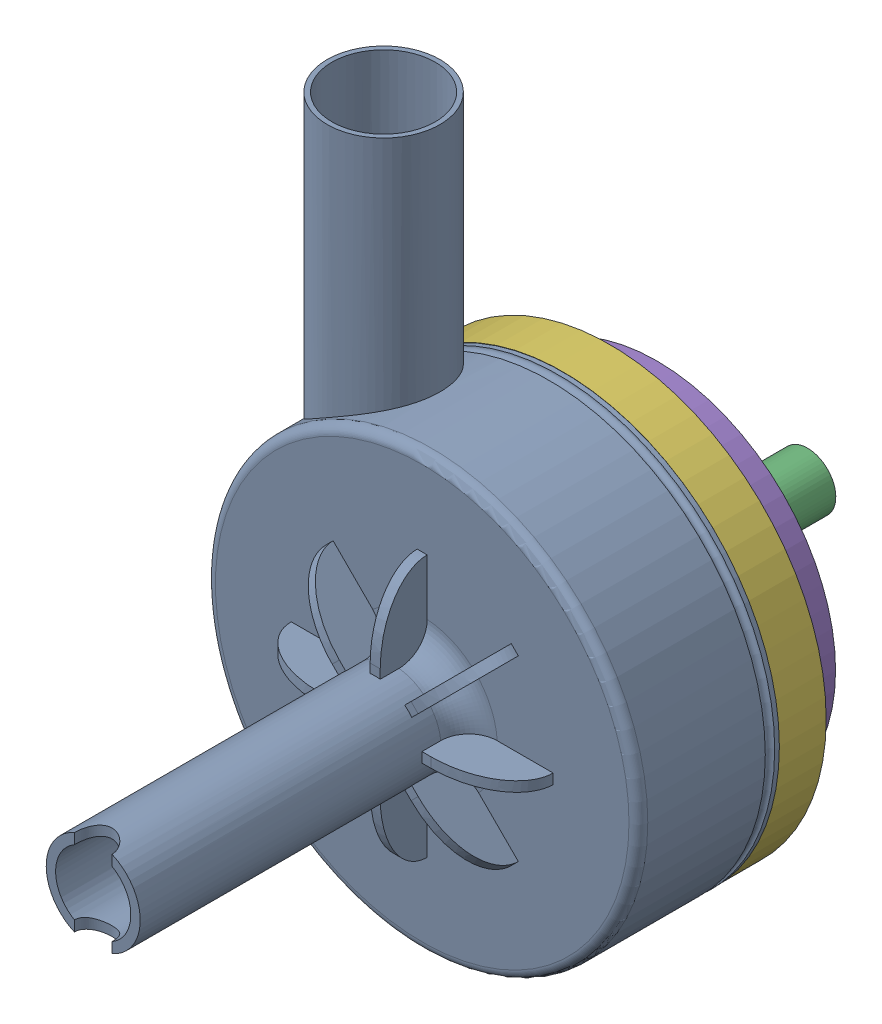
SolidWorks assembly bomba backup all, configuration Default. Lengths in mm.
Overall size (46.06 70 76.13).
5 component instances, 5 part files, 10 mates.
Components (placement in the parent):
- bomba backup-1: bomba backup [Default] at (13.3731 0.3518 -7.2958) size (46 70 50.15)
- hélice backup-1: hélice backup [Default] at (13.3731 0.3518 -5.2958) x (0.145388 -0.989375 0) z (-0.989375 -0.145388 0) size (37.44 12 37.44)
- veio backup-1: veio backup [Default] at (13.3731 0.3518 6.7042) x (-0.145388 0.989375 0) z (0 0 -1) size (6 6 40)
- tampa backup-1: tampa backup [Default] at (13.3493 0.3788 -7.2958) x (-0.999999 0.001285 0) z (0 0 -1) size (46 46 15.02)
- dummy backup-1: dummy backup [Default] at (13.3731 0.3518 -7.2958) x (0.999769 0.021513 0) z (0 0 1) size (38 38 14) (hidden)
Mates (geometry in assembly coordinates):
- Concentric1: concentric aligned: cylinder of bomba backup-1 through (13.3731 0.3518 5.7042) axis (0 0 1) radius 4; cylinder of hélice-1 through (13.3731 0.3518 -5.2958) axis (0 0 1) radius 3
- Coincident1: coincident anti-aligned: plane of bomba backup-1 through (13.3731 0.3518 6.7042) normal (0 0 -1); plane of hélice-1 through (31.1518 2.9764 6.7042) normal (0 0 1)
- Concentric3: concentric aligned: cylinder of hélice-1 through (13.3731 0.3518 -5.2958) axis (0 0 1) radius 3; cylinder of veio backup-1 through (13.3731 0.3518 -33.2958) axis (0 0 1) radius 3
- Coincident3: coincident anti-aligned: plane of hélice-1 through (15.0268 2.8549 -5.2958) normal (-0.989375 -0.145388 0); plane of veio backup-1 through (15.0268 2.8549 -33.2958) normal (0.989375 0.145388 0)
- Coincident4: coincident anti-aligned: plane of hélice-1 through (31.1518 2.9764 -5.2958) normal (0 0 -1); plane of veio backup-1 through (13.3731 0.3518 -5.2958) normal (0 0 1)
- Concentric4: concentric anti-aligned: cylinder of bomba backup-1 through (34.3493 0.3518 -2.2958) axis (0 0 -1) radius 1.5; cylinder of tampa backup-1 through (34.3493 0.3518 -12.2958) axis (0 0 1) radius 1.4957
- Parallel2: parallel aligned: cylinder of veio backup-1 through (13.3731 0.3518 -33.2958) axis (0 0 1) radius 3; cylinder of tampa backup-1 through (13.3493 0.3788 -22.2958) axis (0 0 1) radius 3.5
- Coincident5: coincident anti-aligned: plane of bomba backup-1 through (-11.7379 35.3518 -7.2958) normal (0 0 -1); plane of tampa backup-1 through (13.3493 0.3788 -7.2958) normal (0 0 1)
- Concentric10: concentric aligned: cylinder of bomba backup-1 through (13.3731 0.3518 6.7042) axis (0 0 -1) radius 19; cylinder of dummy backup-1 through (13.3731 0.3518 6.7042) axis (0 0 -1) radius 19
- Coincident6: coincident anti-aligned: plane of bomba backup-1 through (13.3731 0.3518 6.7042) normal (0 0 -1); plane of dummy backup-1 through (13.3731 0.3518 6.7042) normal (0 0 1)
